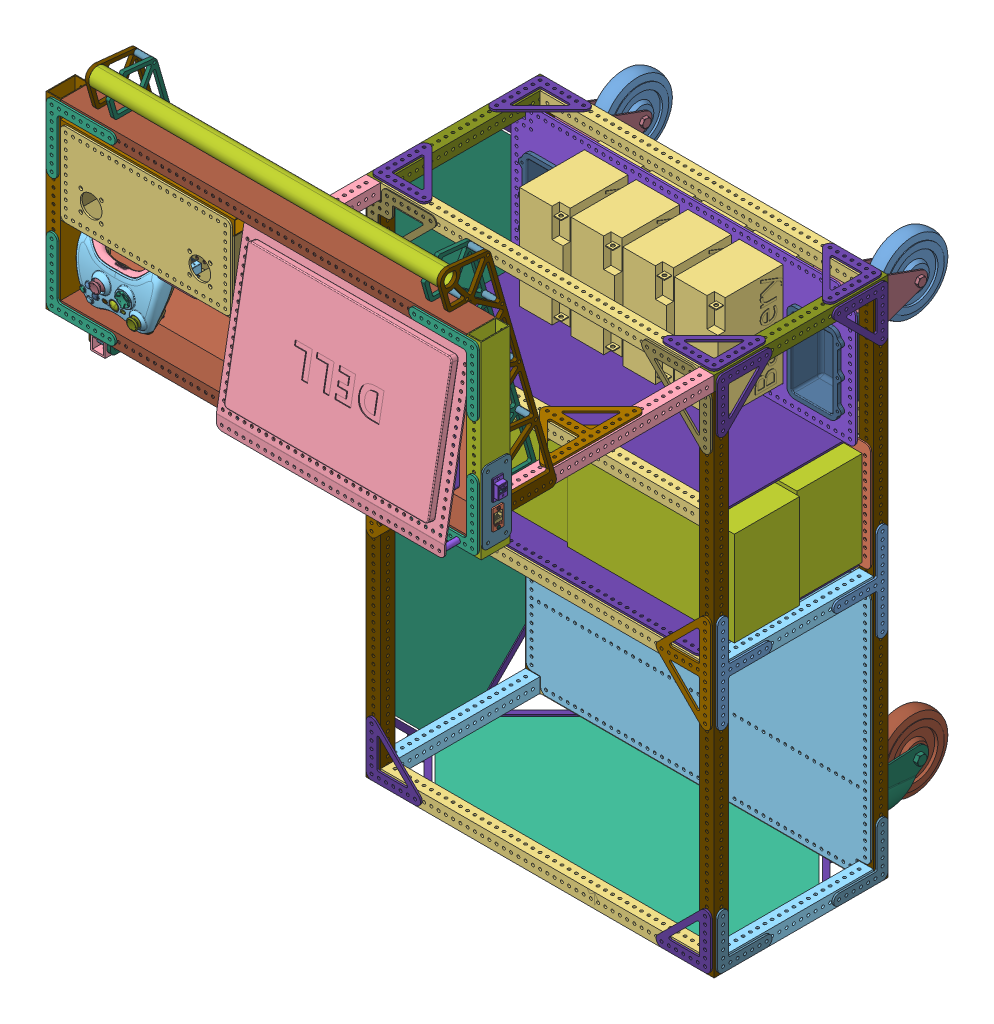
SolidWorks assembly Cart - Assembly, configuration Default. Lengths in mm.
Overall size (775.08 1317.63 991.51).
196 component instances, 79 part files, 0 mates.
Components (placement in the parent):
- Cart - Assembly.step-1: Cart - Assembly.step [Default] at origin size (775.08 1317.63 991.51)
  - Driver Station _1_.step-1: Driver Station _1_.step [Default] at origin size (775.08 330.2 124.28)
    - Part 15.step-1: Part 15.step [Default] at (-383.3431 179.2066 799.273) x (-1 0 0) z (0 0 1) size (10.42 11 14.61)
    - Part 3.step-1: Part 3.step [Default] at (-164.9999 422.8574 791.5272) x (-1 0 0) z (0 0 1) size (298.45 146.05 1.52)
    - 1AA05-019.step-1: 1AA05-019.step [Default] at (264.988 218.7208 790.0032) x (0 0 1) z (1 0 0) size (14.43 10.53 14.2)
    - Part 1.step-1: Part 1.step [Default] at (37.4394 285.4678 825.5184) x (-1 0 0) z (0 0.179137 0.983824) size (358.14 236.22 12.7)
    - 1AA05-019.step-2: 1AA05-019.step [Default] at (-265.3827 271.5089 791.5272) x (0 0 -1) z (0 -1 0) size (14.43 10.53 14.2)
    - Part 20.step-1: Part 20.step [Default] at (-383.3431 179.2066 799.273) x (-1 0 0) z (0 0 1) size (156.66 108.25 81.89)
    - Part 4.step-1: Part 4.step [Default] at (96.1134 336.778 790.0032) x (0 1 0) z (0 0 -1) size (120.65 120.65 3.18)
    - Part 7.step-1: Part 7.step [Default] at (-383.3431 179.2066 799.273) x (-1 0 0) z (0 0 1) size (15.31 16.37 14.57)
    - Part 1-0.step-1: Part 1-0.step [Default] at (104.6391 230.7194 764.6032) x (-1 0 0) z (0 0 1) size (144.78 144.78 53.34)
    - Part 1-1.step-1: Part 1-1.step [Default] at (-685.8256 281.787 790.0032) x (-1 0 0) z (0 0 -1) size (25.4 330.2 50.8)
    - Part 4.step-2: Part 4.step [Default] at (50.7744 281.787 790.0032) x (-1 0 0) z (0 0 -1) size (120.65 120.65 3.18)
    - Part 4.step-3: Part 4.step [Default] at (-326.0346 236.448 790.0032) x (0 -1 0) z (0 0 -1) size (120.65 120.65 3.18)
    - 1AA05-019_1.step-1: 1AA05-019_1.step [Default] at (264.988 218.7208 790.0032) x (0 0 1) z (1 0 0) size (14.43 10.53 14.2)
    - Part 2.step-1: Part 2.step [Default] at (50.7744 281.787 790.0032) x (-1 0 0) z (0 0 -1) size (711.2 25.4 50.8)
    - Part 2-2.step-1: Part 2-2.step [Default] at (-164.9999 422.8574 791.5272) x (-1 0 0) z (0 0 1) size (25.4 101.6 50.8)
    - Part 19.step-1: Part 19.step [Default] at (-383.3431 179.2066 799.273) x (-1 0 0) z (0 0 1) size (31.11 31.05 23.97)
    - 1BC01-008.step-1: 1BC01-008.step [Default] at (264.988 218.7208 790.0032) x (0 0 1) z (1 0 0) size (12.95 1.65 32.89)
    - 1BC01-008.step-2: 1BC01-008.step [Default] at (-265.3827 271.5089 791.5272) x (0 0 -1) z (0 -1 0) size (12.95 1.65 32.89)
    - 91772A106_default.step-1: 91772A106_default.step [Default] at (270.8654 175.488 790.0032) x (0 0 1) z (1 0 0) size (5.56 5.56 8.35)
    - Part 11.step-1: Part 11.step [Default] at (-383.3431 179.2066 799.273) x (-1 0 0) z (0 0 1) size (110.46 24.38 14.2)
    - Part 9.step-1: Part 9.step [Default] at (-383.3431 179.2066 799.273) x (-1 0 0) z (0 0 1) size (8.98 14.34 23.83)
    - Part 10.step-1: Part 10.step [Default] at (-383.3431 179.2066 799.273) x (-1 0 0) z (0 0 1) size (25.31 12.56 10.47)
    - Part 1-3.step-1: Part 1-3.step [Default] at (-144.6234 200.352 779.3011) x (0 -1 0) z (0 0 1) size (43.18 180.34 30.48)
    - ECF-SK.step-1: ECF-SK.step [Default] at (270.8654 175.488 790.0032) x (0 0 1) z (1 0 0) size (19.05 35.56 10.41)
    - Part 2.step-2: Part 2.step [Default] at (50.7745 -23.013 790.0032) x (-1 0 0) z (0 0 -1) size (711.2 25.4 50.8)
    - TDG1026KS-C5E_with depressed top locking clip.step-1: TDG1026KS-C5E_with depressed top locking clip.step [Default] at (270.8654 175.488 790.0032) x (0 0 1) z (1 0 0) size (16.69 21.74 30.48)
    - Part 3-4.step-1: Part 3-4.step [Default] at (-383.3431 179.2066 799.273) x (-1 0 0) z (0 0 1) size (126.17 38.31 35.4)
    - Part 14.step-1: Part 14.step [Default] at (-383.3431 179.2066 799.273) x (-1 0 0) z (0 0 1) size (10.42 10.85 13.95)
    - Part 16.step-1: Part 16.step [Default] at (-383.3431 179.2066 799.273) x (-1 0 0) z (0 0 1) size (9.6 10.48 14.97)
    - Part 8.step-1: Part 8.step [Default] at (787.3744 291.439 790.0032) x (-1 0 0) z (0 0 1) size (25.4 330.2 50.8)
    - 1AG01-065(USB-A HSG_NEW LATCH)_TYPE A.step-1: 1AG01-065(USB-A HSG_NEW LATCH)_TYPE A.step [Default] at (-265.3827 271.5089 791.5272) x (0 0 -1) z (0 -1 0) size (19.05 35.56 16.93)
    - Part 4.step-4: Part 4.step [Default] at (-280.6956 291.439 790.0032) x (1 0 0) z (0 0 -1) size (120.65 120.65 3.18)
    - Part 1-5.step-1: Part 1-5.step [Default] at (-164.9999 422.8574 791.5272) x (-1 0 0) z (0 0 1) size (304.8 25.4 50.8)
    - Part 11-6.step-1: Part 11-6.step [Default] at (-114.3256 291.439 873.8232) x (-1 0 0) z (0 0 1) size (9.52 9.53 33.02)
    - Part 1-7.step-1: Part 1-7.step [Default] at (-383.3431 179.2066 799.273) x (-1 0 0) z (0 0 1) size (17.28 18.16 12.39)
    - Part 5.step-1: Part 5.step [Default] at (-164.9999 422.8574 791.5272) x (-1 0 0) z (0 0 1) size (304.8 25.4 50.8)
    - Part 4-8.step-1: Part 4-8.step [Default] at (-383.3431 179.2066 799.273) x (-1 0 0) z (0 0 1) size (18.35 9.21 5.21)
    - Part 9-9.step-1: Part 9-9.step [Default] at (815.0604 291.439 790.0032) x (-1 0 0) z (0 0 1) size (2.29 127 50.8)
    - 1AM07-030_AS INSTALLED IN ECF504-UAAS.step-1: 1AM07-030_AS INSTALLED IN ECF504-UAAS.step [Default] at (264.988 218.7208 790.0032) x (0 0 1) z (1 0 0) size (6.35 5.21 13)
    - 1AG01-065(USB-A HSG_NEW LATCH)_TYPE A.step-2: 1AG01-065(USB-A HSG_NEW LATCH)_TYPE A.step [Default] at (264.988 218.7208 790.0032) x (0 0 1) z (1 0 0) size (19.05 35.56 16.93)
    - Part 18.step-1: Part 18.step [Default] at (-383.3431 179.2066 799.273) x (-1 0 0) z (0 0 1) size (31.11 31.05 23.97)
    - Part 12.step-1: Part 12.step [Default] at (-383.3431 179.2066 799.273) x (-1 0 0) z (0 0 1) size (8.98 14.34 23.83)
    - Part 6.step-1: Part 6.step [Default] at (-383.3431 179.2066 799.273) x (-1 0 0) z (0 0 1) size (8.12 6.33 12.98)
    - Part 13.step-1: Part 13.step [Default] at (-383.3431 179.2066 799.273) x (-1 0 0) z (0 0 1) size (25.28 12.56 10.47)
    - Part 3-10.step-1: Part 3-10.step [Default] at (50.7744 281.787 790.0032) x (-1 0 0) z (0 0 -1) size (755.65 323.85 1.59)
    - Part 4-11.step-1: Part 4-11.step [Default] at (-164.9999 422.8574 791.5272) x (-1 0 0) z (0 0 1) size (298.45 146.05 3.11)
    - Part 7-12.step-1: Part 7-12.step [Default] at (-191.7956 291.439 790.0032) x (1 0 0) z (0 0 -1) size (400.05 301.34 86.11)
    - 1AG01-067(USB-A COVER_NEW LATCH)_TYPE B.step-1: 1AG01-067(USB-A COVER_NEW LATCH)_TYPE B.step [Default] at (264.988 218.7208 790.0032) x (0 0 1) z (1 0 0) size (16.7 22.54 27.88)
    - Part 2-2.step-2: Part 2-2.step [Default] at (-444.3999 422.8574 791.5272) x (-1 0 0) z (0 0 1) size (25.4 101.6 50.8)
    - 1AM07-030_AS INSTALLED IN ECF504-UAAS.step-2: 1AM07-030_AS INSTALLED IN ECF504-UAAS.step [Default] at (-265.3827 271.5089 791.5272) x (0 0 -1) z (0 -1 0) size (6.35 5.21 13)
    - Part 17.step-1: Part 17.step [Default] at (-383.3431 179.2066 799.273) x (-1 0 0) z (0 0 1) size (23.27 23.91 10.63)
    - 1AA05-019_1.step-2: 1AA05-019_1.step [Default] at (-265.3827 271.5089 791.5272) x (0 0 -1) z (0 -1 0) size (14.43 10.53 14.2)
    - 1AG01-067(USB-A COVER_NEW LATCH)_TYPE B.step-2: 1AG01-067(USB-A COVER_NEW LATCH)_TYPE B.step [Default] at (-265.3827 271.5089 791.5272) x (0 0 -1) z (0 -1 0) size (16.7 22.54 27.88)
    - Part 8-13.step-1: Part 8-13.step [Default] at (-383.3431 179.2066 799.273) x (-1 0 0) z (0 0 1) size (8.12 6.33 12.98)
    - Part 10-14.step-1: Part 10-14.step [Default] at (647.6744 291.439 876.9982) x (-1 0 0) z (0 0 1) size (9.53 9.53 29.84)
    - Part 7-15.step-1: Part 7-15.step [Default] at (-294.0995 283.8148 737.729) x (0 -1 0) z (0 0 1) size (101.6 57.15 47.62)
    - Part 5-16.step-1: Part 5-16.step [Default] at (-383.3431 179.2066 799.273) x (-1 0 0) z (0 0 1) size (10.43 10.97 14.88)
    - 91772A106_default_1.step-1: 91772A106_default_1.step [Default] at (270.8654 175.488 790.0032) x (0 0 1) z (1 0 0) size (5.56 5.56 8.35)
    - Part 2-17.step-1: Part 2-17.step [Default] at (-383.3431 179.2066 799.273) x (-1 0 0) z (0 0 1) size (154.13 106.04 36.91)
    - Part 6-18.step-1: Part 6-18.step [Default] at (-164.9999 422.8574 791.5272) x (-1 0 0) z (0 0 1) size (76.2 2.29 50.8)
  - Part 12-19.step-1: Part 12-19.step [Default] at (-851.5606 301.7229 257.5455) x (0 -1 0) z (0 0 1) size (9.52 25.4 9.53)
  - Part 12-19.step-2: Part 12-19.step [Default] at (-851.5606 199.1194 227.9957) x (0 -1 0) z (0 0 1) size (9.52 25.4 9.53)
  - 2370T15.step-1: 2370T15.step [Default] at (-356.2605 -716.687 23.2407) x (0 -1 0) z (-1 0 0) size (100.81 110.33 73.03)
  - Part 8-20.step-1: Part 8-20.step [Default] at (-419.7605 -335.687 26.4157) x (1 0 0) z (0 0 1) size (120.65 146.05 3.17)
  - Part 5-21.step-1: Part 5-21.step [Default] at (-419.7605 -335.687 331.2157) x (1 0 0) z (0 0 -1) size (95.25 3.17 95.25)
  - Part 5-21.step-2: Part 5-21.step [Default] at (189.8395 -335.687 26.4157) x (0 0 1) z (-1 0 0) size (95.25 3.17 95.25)
  - Part 5-21.step-3: Part 5-21.step [Default] at (37.4395 -792.887 26.4157) x (0 0 1) z (0 1 0) size (95.25 3.17 95.25)
  - Part 12-19.step-3: Part 12-19.step [Default] at (-267.3606 -11.1222 235.9022) x (0 -1 0) z (0 0 1) size (9.52 25.4 9.53)
  - Part 17-22.step-1: Part 17-22.step [Default] at (189.8395 -335.687 305.8157) x (1 0 0) z (0 0 1) size (25.4 889 25.4)
  - Part 12-19.step-4: Part 12-19.step [Default] at (-851.5606 234.8375 305.8157) x (0 -1 0) z (0 0 1) size (9.52 25.4 9.53)
  - Part 5-21.step-4: Part 5-21.step [Default] at (650.2144 121.513 26.4157) x (0 -1 0) z (0 0 1) size (95.25 3.17 95.25)
  - Part 12-19.step-5: Part 12-19.step [Default] at (-267.3606 -11.1222 261.3022) x (0 -1 0) z (0 0 1) size (9.52 25.4 9.53)
  - 2370T25.step-1: 2370T25.step [Default] at (-356.2606 45.313 23.2407) x (0 -1 0) z (-1 0 0) size (127 127 38.1)
  - Part 12-19.step-6: Part 12-19.step [Default] at (-267.3606 301.7229 257.5455) x (0 -1 0) z (0 0 1) size (9.52 25.4 9.53)
  - Part 27.step-1: Part 27.step [Default] at (-640.7201 699.8947 51.8157) x (1 0 0) z (0 0 1) size (603.25 190.5 2.29)
  - Part 12-19.step-7: Part 12-19.step [Default] at (-267.3606 -11.1222 172.4022) x (0 -1 0) z (0 0 1) size (9.52 25.4 9.53)
  - Part 2-23.step-1: Part 2-23.step [Default] at (-419.7605 -335.687 305.8157) x (1 0 0) z (0 0 1) size (558.8 25.4 25.4)
  - Part 2-23.step-2: Part 2-23.step [Default] at (-419.7606 553.313 305.8157) x (1 0 0) z (0 0 1) size (558.8 25.4 25.4)
  - Part 15-24.step-1: Part 15-24.step [Default] at (-419.7605 -335.687 26.4157) x (1 0 0) z (0 0 1) size (603.25 234.95 3.17)
  - Part 12-19.step-8: Part 12-19.step [Default] at (-851.5606 -11.1222 299.4022) x (0 -1 0) z (0 0 1) size (9.52 25.4 9.53)
  - Part 8-20.step-2: Part 8-20.step [Default] at (62.8395 -335.687 26.4157) x (1 0 0) z (0 0 1) size (120.65 146.05 3.17)
  - Part 3-25.step-1: Part 3-25.step [Default] at (164.4395 108.813 26.4155) x (1 0 0) z (0 0 1) size (25.4 25.4 254)
  - Part 23.step-1: Part 23.step [Default] at (-422.9355 -1536.9512 393.0537) x (0 -1 0) z (1 0 0) size (908.05 298.45 3.17)
  - Part 21.step-1: Part 21.step [Default] at (-992.5832 -4.5735 180.6839) size (292.1 165.1 114.3)
  - Part 12-19.step-9: Part 12-19.step [Default] at (-267.3606 -11.1222 324.8022) x (0 -1 0) z (0 0 1) size (9.52 25.4 9.53)
  - Part 22.step-1: Part 22.step [Default] at (280.1012 -1097.2031 77.2157) x (0 1 0) z (0 0 1) size (234.95 603.25 3.17)
  - Part 7-26.step-1: Part 7-26.step [Default] at (-419.7605 -335.687 509.0157) x (1 0 0) z (0 0 1) size (95.25 3.17 171.45)
  - Part 12-19.step-10: Part 12-19.step [Default] at (-267.3606 234.8375 305.8157) x (0 -1 0) z (0 0 1) size (9.52 25.4 9.53)
  - Part 28.step-1: Part 28.step [Default] at (-868.8515 235.5172 80.3907) x (0 1 0) z (0 0 1) size (139.32 94.87 53.34)
  - Part 12-19.step-11: Part 12-19.step [Default] at (-851.5606 -11.1222 248.6022) x (0 -1 0) z (0 0 1) size (9.52 25.4 9.53)
  - 2370T15-27.step-1: 2370T15-27.step [Default] at (126.3395 -716.687 23.2407) x (0 -1 0) z (-1 0 0) size (127 127 34.29)
  - Part 12-19.step-12: Part 12-19.step [Default] at (-267.3606 -11.1222 337.5022) x (0 -1 0) z (0 0 1) size (9.52 25.4 9.53)
  - Part 6-28.step-1: Part 6-28.step [Default] at (-267.3606 -18.187 334.3907) x (0 0 1) z (0 1 0) size (3.17 120.65 120.65)
  - 2370T25-29.step-1: 2370T25-29.step [Default] at (126.3394 45.313 23.2407) x (0 -1 0) z (-1 0 0) size (104.78 106.38 74.61)
  - Part 20-30.step-1: Part 20-30.step [Default] at (653.3895 -792.887 331.2157) x (0 1 0) z (0 0 -1) size (95.25 3.18 95.25)
  - Part 10-31.step-1: Part 10-31.step [Default] at (-819.8106 121.513 305.8157) x (0 -1 0) z (0 0 1) size (420.79 6.41 198.77)
  - Part 5-21.step-5: Part 5-21.step [Default] at (-419.7605 -335.687 331.2157) x (0 0 -1) z (1 0 0) size (95.25 3.17 95.25)
  - Part 5-21.step-6: Part 5-21.step [Default] at (-419.7605 -335.687 26.4157) x (1 0 0) z (0 0 1) size (95.25 3.17 95.25)
  - Part 5-21.step-7: Part 5-21.step [Default] at (189.8395 -335.687 26.4157) x (-1 0 0) z (0 0 1) size (95.25 3.17 95.25)
  - Part 12-19.step-13: Part 12-19.step [Default] at (-851.5606 -11.1222 197.8022) x (0 -1 0) z (0 0 1) size (9.52 25.4 9.53)
  - Part 7-26.step-2: Part 7-26.step [Default] at (-419.7605 -310.287 -433.9593) x (1 0 0) z (0 -1 0) size (95.25 3.17 171.45)
  - Part 16-32.step-1: Part 16-32.step [Default] at (-419.7606 524.3115 1.0157) x (1 0 0) z (0 0 1) size (25.4 25.4 304.8)
  - Part 12-19.step-14: Part 12-19.step [Default] at (-851.5606 -11.1222 337.5022) x (0 -1 0) z (0 0 1) size (9.52 25.4 9.53)
  - Part 25.step-1: Part 25.step [Default] at (-1366.5368 -119.787 -655.3006) x (-1 0 0) z (0 -1 0) size (552.45 298.45 3.17)
  - Part 9-33.step-1: Part 9-33.step [Default] at (-883.3106 121.513 305.8157) x (0 -1 0) z (0 0 1) size (422.28 6.35 203.2)
  - Part 14-34.step-1: Part 14-34.step [Default] at (-419.7606 -81.687 -157.7343) x (1 0 0) z (0 -1 0) size (95.25 3.18 171.45)
  - Part 6-28.step-2: Part 6-28.step [Default] at (-280.0605 -335.687 332.8032) x (0 0 1) z (-1 0 0) size (3.17 120.65 120.65)
  - Part 18-35.step-1: Part 18-35.step [Default] at (-851.6622 96.113 839.2157) x (0 1 0) z (0 0 -1) size (18.8 18.8 241.3)
  - Part 9-33.step-2: Part 9-33.step [Default] at (-267.3606 121.513 305.8157) x (0 -1 0) z (0 0 1) size (422.28 6.35 203.2)
  - Part 5-21.step-8: Part 5-21.step [Default] at (-419.7605 -792.887 791.5907) x (0 1 0) z (1 0 0) size (95.25 3.17 95.25)
  - Part 21.step-2: Part 21.step [Default] at (-1280.6335 0.1933 179.0034) size (292.1 165.1 114.3)
  - Part 12-19.step-15: Part 12-19.step [Default] at (-267.3606 -11.1222 197.8022) x (0 -1 0) z (0 0 1) size (9.52 25.4 9.53)
  - Part 12-19.step-16: Part 12-19.step [Default] at (-851.5606 -11.1222 210.5022) x (0 -1 0) z (0 0 1) size (9.52 25.4 9.53)
  - Simplified Battery.step-1: Simplified Battery.step [Default] at (-288.7918 8.3243 109.9817) x (0 1 0) z (1 0 0) size (180.34 167.13 76.99)
  - Part 12-19.step-17: Part 12-19.step [Default] at (-267.3606 -11.1222 210.5022) x (0 -1 0) z (0 0 1) size (9.52 25.4 9.53)
  - Part 3-25.step-2: Part 3-25.step [Default] at (-419.7606 108.813 26.4157) x (1 0 0) z (0 0 1) size (25.4 25.4 254)
  - Part 2-23.step-3: Part 2-23.step [Default] at (-419.7605 -208.687 26.4157) x (1 0 0) z (0 0 1) size (558.8 25.4 25.4)
  - Part 3-25.step-3: Part 3-25.step [Default] at (164.4395 -335.687 26.4157) x (1 0 0) z (0 0 1) size (25.4 25.4 254)
  - Part 21.step-3: Part 21.step [Default] at (-1277.9322 -4.2432 59.69) size (292.1 165.1 114.3)
  - Part 12-19.step-18: Part 12-19.step [Default] at (-851.5606 -11.1222 350.2022) x (0 -1 0) z (0 0 1) size (9.52 25.4 9.53)
  - Part 12-19.step-19: Part 12-19.step [Default] at (-851.5606 339.7153 319.4491) x (0 -1 0) z (0 0 1) size (9.52 25.4 9.53)
  - Part 5-21.step-9: Part 5-21.step [Default] at (189.8395 -792.887 791.5907) x (-1 0 0) z (0 1 0) size (95.25 3.17 95.25)
  - Part 4-36.step-1: Part 4-36.step [Default] at (-851.5606 121.513 305.8157) x (0 -1 0) z (0 0 1) size (25.4 25.4 482.6)
  - Part 5-21.step-10: Part 5-21.step [Default] at (37.4394 121.513 331.2157) x (0 0 -1) z (0 -1 0) size (95.25 3.17 95.25)
  - Part 12-19.step-20: Part 12-19.step [Default] at (-267.3606 121.513 305.8157) x (0 -1 0) z (0 0 1) size (9.52 25.4 9.53)
  - Simplified Battery.step-2: Simplified Battery.step [Default] at (-17.3293 8.3243 109.9817) x (0 1 0) z (1 0 0) size (180.34 167.13 76.99)
  - Part 12-19.step-21: Part 12-19.step [Default] at (-267.3606 -11.1222 350.2022) x (0 -1 0) z (0 0 1) size (9.52 25.4 9.53)
  - Part 2-23.step-4: Part 2-23.step [Default] at (-419.7606 108.813 26.4157) x (1 0 0) z (0 0 1) size (558.8 25.4 25.4)
  - Part 21.step-4: Part 21.step [Default] at (-1003.0985 -4.5735 60.493) size (292.1 165.1 114.3)
  - Part 17-22.step-2: Part 17-22.step [Default] at (189.8395 -335.687 26.4157) x (1 0 0) z (0 0 1) size (25.4 889 25.4)
  - Part 25.step-2: Part 25.step [Default] at (-1366.5368 -319.812 -655.3006) x (-1 0 0) z (0 -1 0) size (552.45 298.45 3.17)
  - Part 5-21.step-11: Part 5-21.step [Default] at (189.8395 -335.687 331.2157) x (0 0 -1) z (-1 0 0) size (95.25 3.17 95.25)
  - Part 12-19.step-22: Part 12-19.step [Default] at (-851.5606 -11.1222 261.3022) x (0 -1 0) z (0 0 1) size (9.52 25.4 9.53)
  - Part 2-23.step-5: Part 2-23.step [Default] at (-419.7605 -335.687 305.8157) x (1 0 0) z (0 0 1) size (558.8 25.4 25.4)
  - Part 17-22.step-3: Part 17-22.step [Default] at (-394.3605 -335.687 26.4157) x (1 0 0) z (0 0 1) size (25.4 889 25.4)
  - Part 12-19.step-23: Part 12-19.step [Default] at (-851.5606 -11.1222 324.8022) x (0 -1 0) z (0 0 1) size (9.52 25.4 9.53)
  - Part 7-26.step-3: Part 7-26.step [Default] at (189.8395 -364.262 559.8157) x (-1 0 0) z (0 0 -1) size (95.25 3.17 171.45)
  - Part 12-19.step-24: Part 12-19.step [Default] at (-267.3606 -11.1222 248.6022) x (0 -1 0) z (0 0 1) size (9.52 25.4 9.53)
  - Part 5-21.step-12: Part 5-21.step [Default] at (37.4395 -792.887 331.2157) x (0 1 0) z (0 0 -1) size (95.25 3.17 95.25)
  - Part 2-23.step-6: Part 2-23.step [Default] at (-419.7606 108.813 305.8157) x (1 0 0) z (0 0 1) size (558.8 25.4 25.4)
  - Part 12-19.step-25: Part 12-19.step [Default] at (-267.3606 -11.1222 185.1022) x (0 -1 0) z (0 0 1) size (9.52 25.4 9.53)
  - Part 12-19.step-26: Part 12-19.step [Default] at (-851.5606 -11.1222 286.7022) x (0 -1 0) z (0 0 1) size (9.52 25.4 9.53)
  - Part 3-25.step-4: Part 3-25.step [Default] at (-419.7605 -335.687 26.4157) x (1 0 0) z (0 0 1) size (25.4 25.4 254)
  - Part 12-19.step-27: Part 12-19.step [Default] at (-851.5606 -11.1222 172.4022) x (0 -1 0) z (0 0 1) size (9.52 25.4 9.53)
  - Part 4-36.step-2: Part 4-36.step [Default] at (164.4395 -335.687 305.8157) x (1 0 0) z (0 0 1) size (25.4 25.4 482.6)
  - Part 26.step-1: Part 26.step [Default] at (-946.3177 297.688 54.1017) x (0 1 0) z (0 0 1) size (463.55 603.25 2.29)
  - Part 17-22.step-4: Part 17-22.step [Default] at (-394.3605 -335.687 305.8157) x (1 0 0) z (0 0 1) size (25.4 889 25.4)
  - Part 12-19.step-28: Part 12-19.step [Default] at (-267.3606 -11.1222 274.0022) x (0 -1 0) z (0 0 1) size (9.52 25.4 9.53)
  - Part 2-23.step-7: Part 2-23.step [Default] at (-419.7606 337.413 26.4157) x (1 0 0) z (0 0 1) size (558.8 25.4 25.4)
  - Part 12-19.step-29: Part 12-19.step [Default] at (-851.5606 -11.1222 312.1022) x (0 -1 0) z (0 0 1) size (9.52 25.4 9.53)
  - Part 12-19.step-30: Part 12-19.step [Default] at (-851.5606 -11.1222 274.0022) x (0 -1 0) z (0 0 1) size (9.52 25.4 9.53)
  - Simplified Battery.step-3: Simplified Battery.step [Default] at (-198.3043 8.3243 109.9817) x (0 1 0) z (1 0 0) size (180.34 167.13 76.99)
  - Part 12-19.step-31: Part 12-19.step [Default] at (-267.3606 199.1194 227.9957) x (0 -1 0) z (0 0 1) size (9.52 25.4 9.53)
  - Part 5-21.step-13: Part 5-21.step [Default] at (-419.7606 581.888 26.4157) x (1 0 0) z (0 0 1) size (95.25 3.17 95.25)
  - Part 2-23.step-8: Part 2-23.step [Default] at (-419.7606 553.313 521.7157) x (1 0 0) z (0 0 1) size (558.8 25.4 25.4)
  - Part 12-19.step-32: Part 12-19.step [Default] at (-267.3606 -11.1222 223.2022) x (0 -1 0) z (0 0 1) size (9.52 25.4 9.53)
  - Part 2-23.step-9: Part 2-23.step [Default] at (-419.7605 -335.687 26.4157) x (1 0 0) z (0 0 1) size (558.8 25.4 25.4)
  - Part 7-26.step-4: Part 7-26.step [Default] at (189.8395 -361.087 -433.9593) x (-1 0 0) z (0 1 0) size (95.25 3.17 171.45)
  - Part 28.step-2: Part 28.step [Default] at (638.9304 -273.7961 80.3907) x (0 -1 0) z (0 0 1) size (139.32 94.87 53.34)
  - Part 18-35.step-2: Part 18-35.step [Default] at (189.7379 -335.687 839.2157) x (-1 0 0) z (0 0 -1) size (18.8 18.8 241.3)
  - Simplified Battery.step-4: Simplified Battery.step [Default] at (-107.8168 8.3243 109.9817) x (0 1 0) z (1 0 0) size (180.34 167.13 76.99)
  - 2370T15-27.step-2: 2370T15-27.step [Default] at (-356.2605 -716.687 23.2407) x (0 -1 0) z (-1 0 0) size (127 127 34.29)
  - Part 12-19.step-33: Part 12-19.step [Default] at (-267.3606 388.1942 282.6131) x (0 -1 0) z (0 0 1) size (9.52 25.4 9.53)
  - 2370T15.step-2: 2370T15.step [Default] at (126.3395 -716.687 23.2407) x (0 -1 0) z (-1 0 0) size (100.81 110.33 73.03)
  - Part 12-19.step-34: Part 12-19.step [Default] at (-851.5606 -11.1222 223.2022) x (0 -1 0) z (0 0 1) size (9.52 25.4 9.53)
  - Part 7-26.step-5: Part 7-26.step [Default] at (189.8394 581.888 509.0157) x (-1 0 0) z (0 0 1) size (95.25 3.17 171.45)
  - Part 12-19.step-35: Part 12-19.step [Default] at (-267.3606 -11.1222 299.4022) x (0 -1 0) z (0 0 1) size (9.52 25.4 9.53)
  - Part 14-34.step-2: Part 14-34.step [Default] at (653.3895 -310.287 26.4157) x (0 0 1) z (0 -1 0) size (95.25 3.18 171.45)
  - Part 12-19.step-36: Part 12-19.step [Default] at (-851.5606 121.513 305.8157) x (0 -1 0) z (0 0 1) size (9.52 25.4 9.53)
  - Part 12-19.step-37: Part 12-19.step [Default] at (-851.5606 -11.1222 185.1022) x (0 -1 0) z (0 0 1) size (9.52 25.4 9.53)
  - Part 20-30.step-2: Part 20-30.step [Default] at (653.3895 -792.887 26.4157) x (0 0 1) z (0 1 0) size (95.25 3.18 95.25)
  - Part 12-19.step-38: Part 12-19.step [Default] at (-267.3606 -11.1222 286.7022) x (0 -1 0) z (0 0 1) size (9.52 25.4 9.53)
  - Part 12-19.step-39: Part 12-19.step [Default] at (-851.5606 388.1942 282.6131) x (0 -1 0) z (0 0 1) size (9.52 25.4 9.53)
  - Part 5-21.step-14: Part 5-21.step [Default] at (-880.1356 121.513 26.4157) x (0 0 1) z (0 -1 0) size (95.25 3.17 95.25)
  - Part 7-26.step-6: Part 7-26.step [Default] at (189.8395 -310.287 791.5907) x (-1 0 0) z (0 -1 0) size (95.25 3.17 171.45)
  - Part 5-21.step-15: Part 5-21.step [Default] at (189.8395 -1253.262 331.2157) x (0 0 -1) z (-1 0 0) size (95.25 3.17 95.25)
  - Part 12-19.step-40: Part 12-19.step [Default] at (-267.3606 339.7153 319.4491) x (0 -1 0) z (0 0 1) size (9.52 25.4 9.53)
  - Part 12-19.step-41: Part 12-19.step [Default] at (-851.5606 96.8254 198.535) x (0 -1 0) z (0 0 1) size (9.52 25.4 9.53)
  - Part 7-26.step-7: Part 7-26.step [Default] at (-419.7605 -361.087 791.5907) x (1 0 0) z (0 1 0) size (95.25 3.17 171.45)
  - Part 5-21.step-16: Part 5-21.step [Default] at (-267.3606 121.513 331.2157) x (0 -1 0) z (0 0 -1) size (95.25 3.17 95.25)
  - Part 2-23.step-10: Part 2-23.step [Default] at (-419.7606 337.413 305.8157) x (1 0 0) z (0 0 1) size (558.8 25.4 25.4)
  - 2370T25-29.step-2: 2370T25-29.step [Default] at (-356.2606 45.313 23.2407) x (0 -1 0) z (-1 0 0) size (104.78 106.38 74.61)
  - Part 16-32.step-2: Part 16-32.step [Default] at (164.4394 524.3115 1.0157) x (1 0 0) z (0 0 1) size (25.4 25.4 304.8)
  - Part 2-23.step-11: Part 2-23.step [Default] at (-419.7606 553.313 26.4157) x (1 0 0) z (0 0 1) size (558.8 25.4 25.4)
  - 2370T25.step-2: 2370T25.step [Default] at (126.3394 45.313 23.2407) x (0 -1 0) z (-1 0 0) size (127 127 38.1)
  - Part 24.step-1: Part 24.step [Default] at (982.2646 -792.887 476.5476) x (1 0 0) z (0 -1 0) size (603.25 298.45 3.17)
  - Part 11-37.step-1: Part 11-37.step [Default] at (37.4394 121.513 1296.4157) x (0 -1 0) z (0 0 -1) size (32.19 609.6 32.35)
  - Part 7-26.step-8: Part 7-26.step [Default] at (-419.7605 -364.262 509.0157) x (1 0 0) z (0 0 1) size (95.25 3.17 171.45)
  - Part 10-31.step-2: Part 10-31.step [Default] at (-267.3606 121.513 305.8157) x (0 -1 0) z (0 0 1) size (420.79 6.41 198.77)
  - Part 12-19.step-42: Part 12-19.step [Default] at (-267.3606 -11.1222 312.1022) x (0 -1 0) z (0 0 1) size (9.52 25.4 9.53)
  - Part 14-34.step-3: Part 14-34.step [Default] at (189.8394 -132.487 -157.7343) x (-1 0 0) z (0 1 0) size (95.25 3.18 171.45)
  - Part 14-34.step-4: Part 14-34.step [Default] at (-270.5355 -310.287 331.2157) x (0 0 -1) z (0 -1 0) size (95.25 3.18 171.45)
  - Part 12-19.step-43: Part 12-19.step [Default] at (-851.5606 -11.1222 235.9022) x (0 -1 0) z (0 0 1) size (9.52 25.4 9.53)
  - Part 12-19.step-44: Part 12-19.step [Default] at (-267.3606 96.8254 198.535) x (0 -1 0) z (0 0 1) size (9.52 25.4 9.53)
